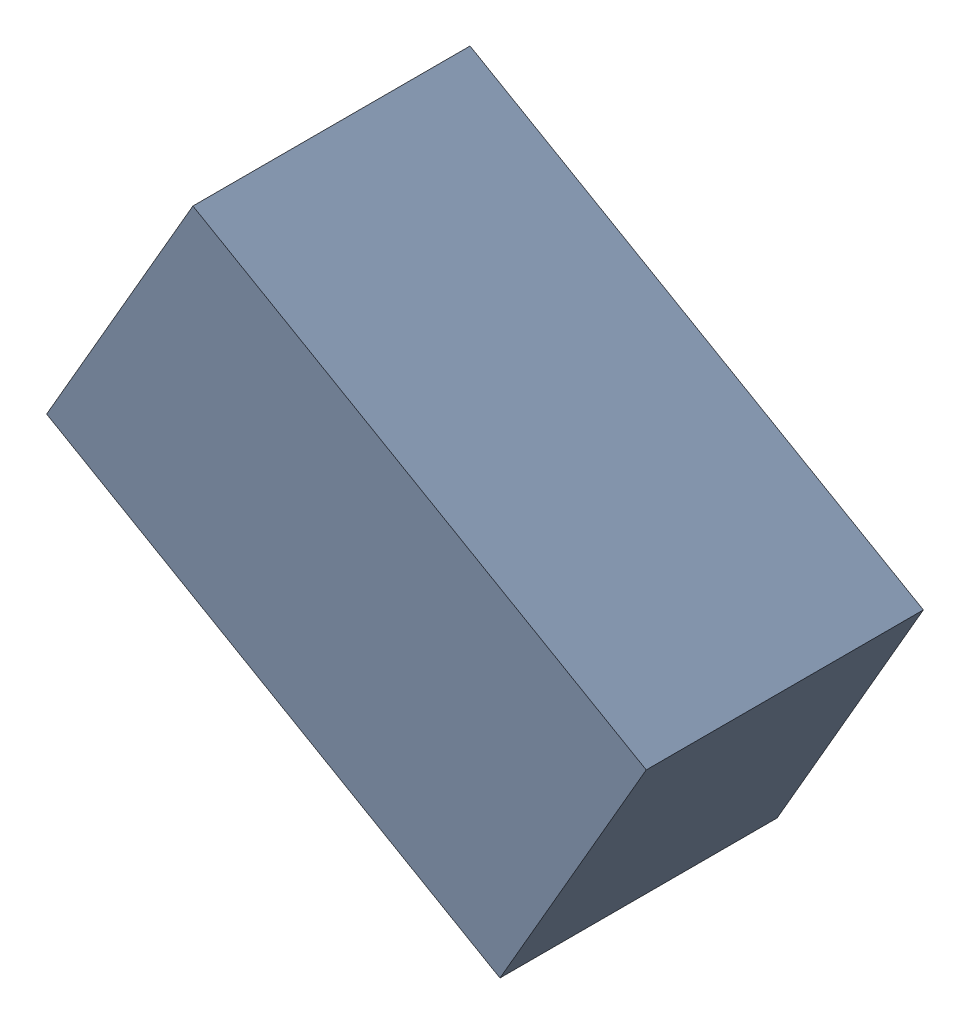
SolidWorks assembly R3_TDA3, configuration Standard. Lengths in mm.
Overall size (1.95 1.67 0.9).
2 component instances, 1 part files, 0 mates.
Components (placement in the parent):
- 885544144-1: 885544144 [Standard] at (42.4085 -32.9376 0) size (1.95 1.67 0.9)
  - Extruded_14-1: Extruded_14 [Standard] at origin size (1.95 1.67 0.9)
